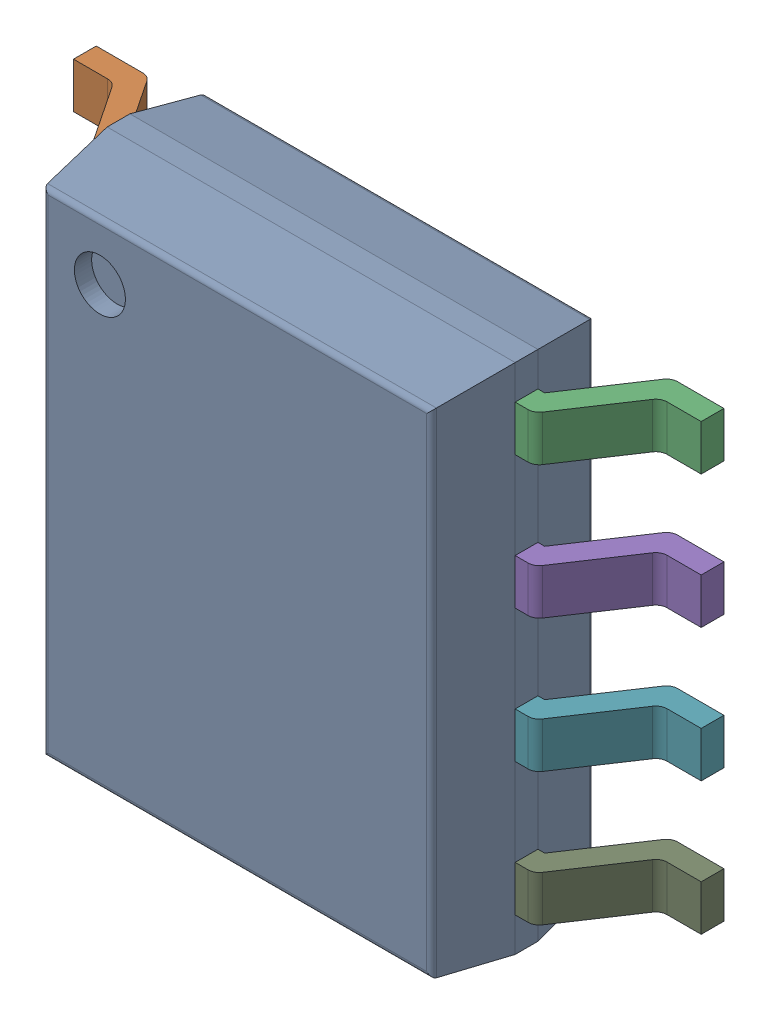
SolidWorks assembly 6348795168_1.step, configuration Default. Lengths in mm.
Overall size (6 4.9 1.65).
3 component instances, 3 part files, 0 mates.
Components (placement in the parent):
- Body-6_1.step-3: Body-6_1.step [Default] at origin size (3.9 4.9 1.55)
- PinsArrayLR_1.step-3: PinsArrayLR_1.step [Default] at origin size (6 4.24 0.95)
- ThermalPad_1.step-3: ThermalPad_1.step [Default] at (-1.045 -1.045 0) size (2.09 2.09 0.1)
